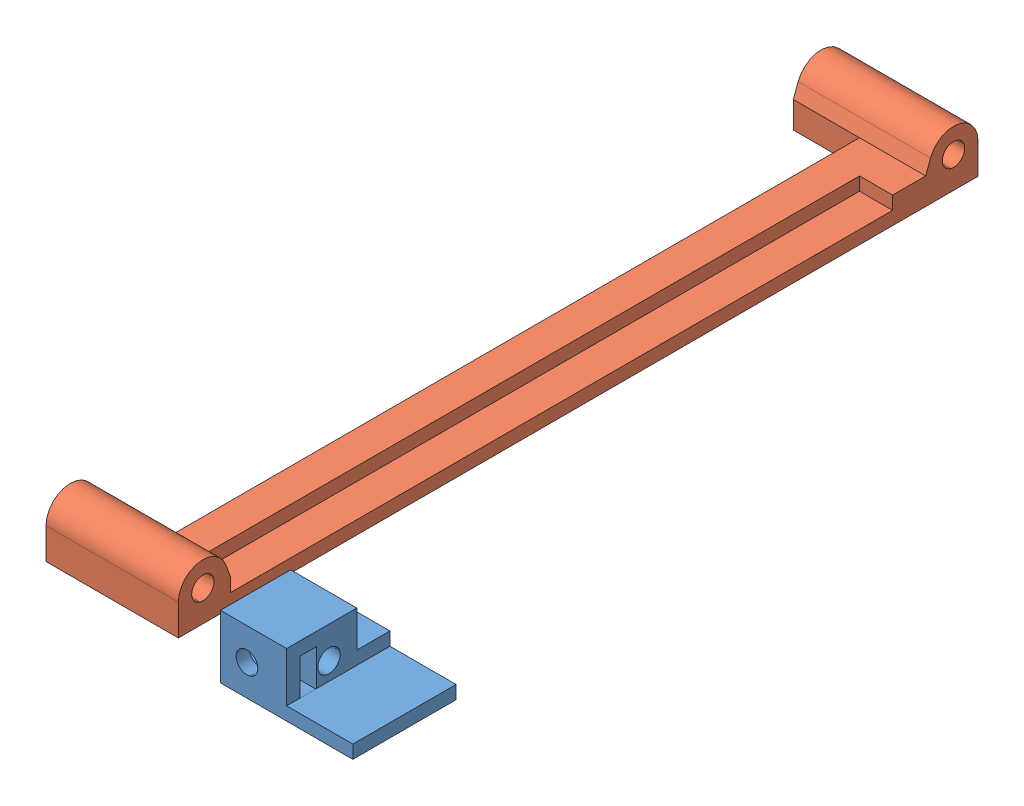
SolidWorks assembly Montagem1, configuration Valor predeterminado. Lengths in mm.
Overall size (49.06 9.5 123.5).
2 component instances, 2 part files, 2 mates.
Components (placement in the parent):
- fixed part-1: fixed part [Valor predeterminado] at (-12.6515 -4.2541 126.2) size (20 9.5 15.6)
- sliding part-1: sliding part [Valor predeterminado] at (-21.7076 -4.2541 178.7) x (-1 0 0) z (0 0 -1) size (20 8.4 120.8)
Mates (geometry in assembly coordinates):
- Concêntrico1: concentric aligned: cylinder of fixed part-1 through (-12.6515 0.4459 182.9) axis (1 0 0) radius 1.7; cylinder of sliding part-1 through (-41.7076 0.4459 182.9) axis (1 0 0) radius 1.7
- Coincidente1: coincident: cylinder of fixed part-1 through (-12.6515 0.4459 69.5) axis (1 0 0) radius 1.7; circle of sliding part-1
